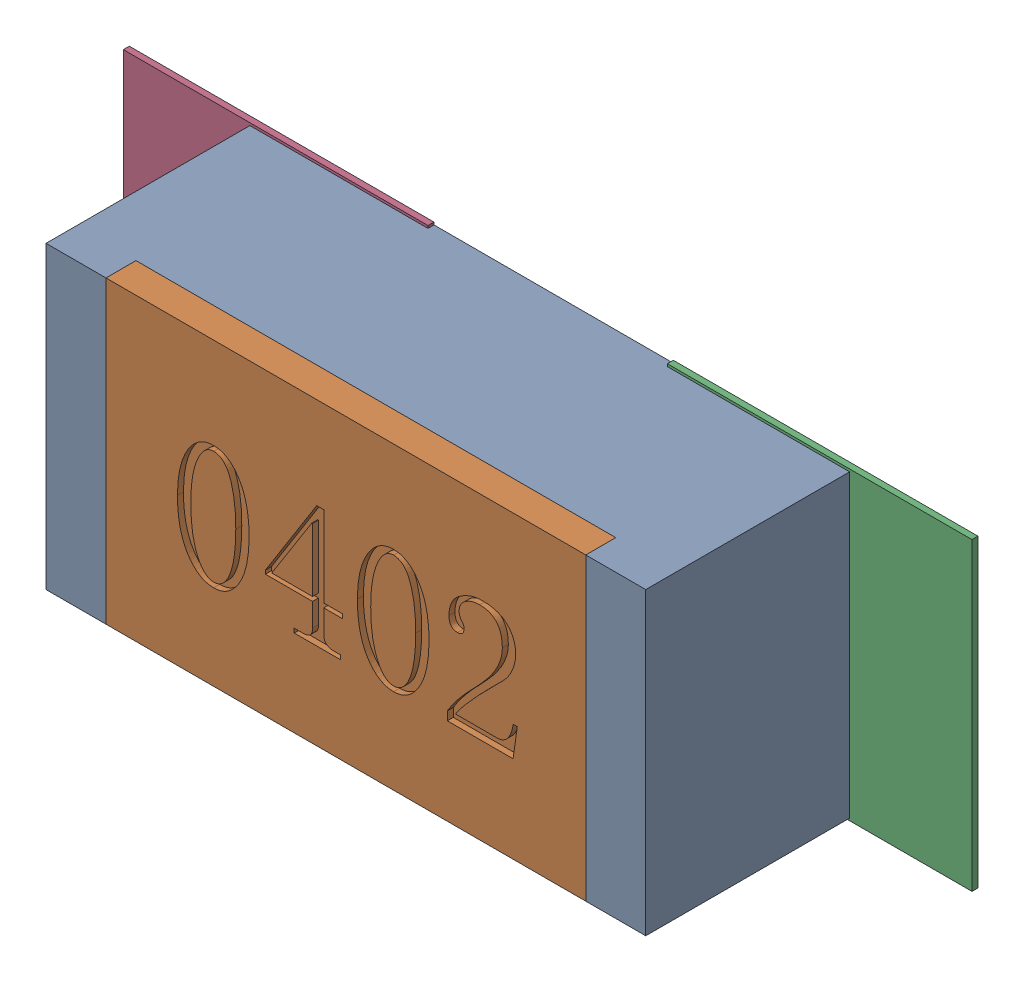
SolidWorks assembly R26, configuration Défaut. Lengths in mm.
Overall size (1.42 0.51 0.35).
5 component instances, 2 part files, 0 mates.
Components (placement in the parent):
- R0402-1: R0402 [Défaut] at (20.0406 -26.3653 0) x (1 0 0) z (0 0 1) size (1 0.5 0.35)
- 6504207776-1: 6504207776 [Défaut] at (20.4906 -26.3652 0) size (0.51 0.51 0.01)
  - Extruded-1: Extruded [Défaut] at origin size (0.51 0.51 0.01)
- 6504207776-2: 6504207776 [Défaut] at (19.5835 -26.3652 0) size (0.51 0.51 0.01)
  - Extruded-1: Extruded [Défaut] at origin size (0.51 0.51 0.01)
